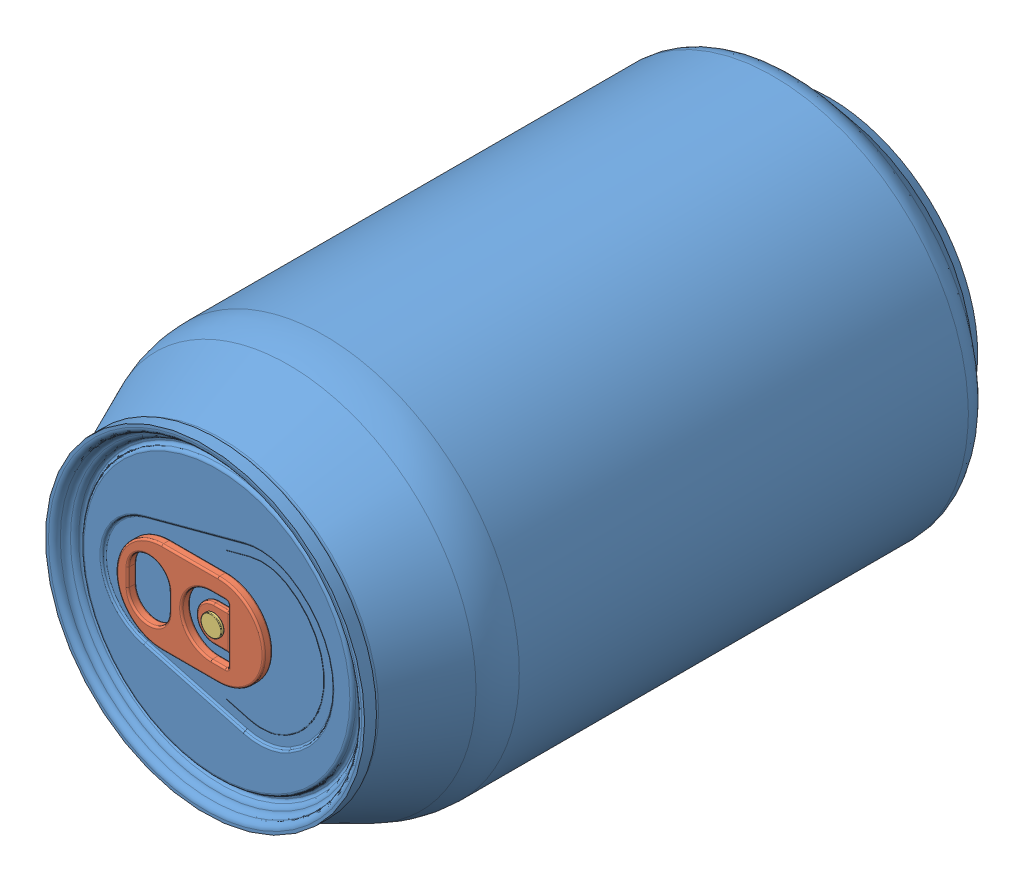
SolidWorks assembly 33cl-CAN, configuration Default. Lengths in mm.
Overall size (66 66 106).
4 component instances, 3 part files, 0 mates.
Components (placement in the parent):
- 33cl-CAN.stp-1: 33cl-CAN.stp [Default] at origin size (66 66 106)
  - 33cl-CAN_1.stp-1: 33cl-CAN_1.stp [Default] at (26.7922 30.6101 -52.5247) size (66 66 106)
  - CAN-cap.stp-1: CAN-cap.stp [Default] at (35.7278 22.8601 52.4753) x (-1 0 0) z (0 0 -1) size (25 15.5 1.5)
  - Cap-lock.stp-1: Cap-lock.stp [Default] at (26.7922 30.6101 50.8753) x (0.431999 0.901874 0) z (0 0 1) size (3.5 3.5 2.1)
